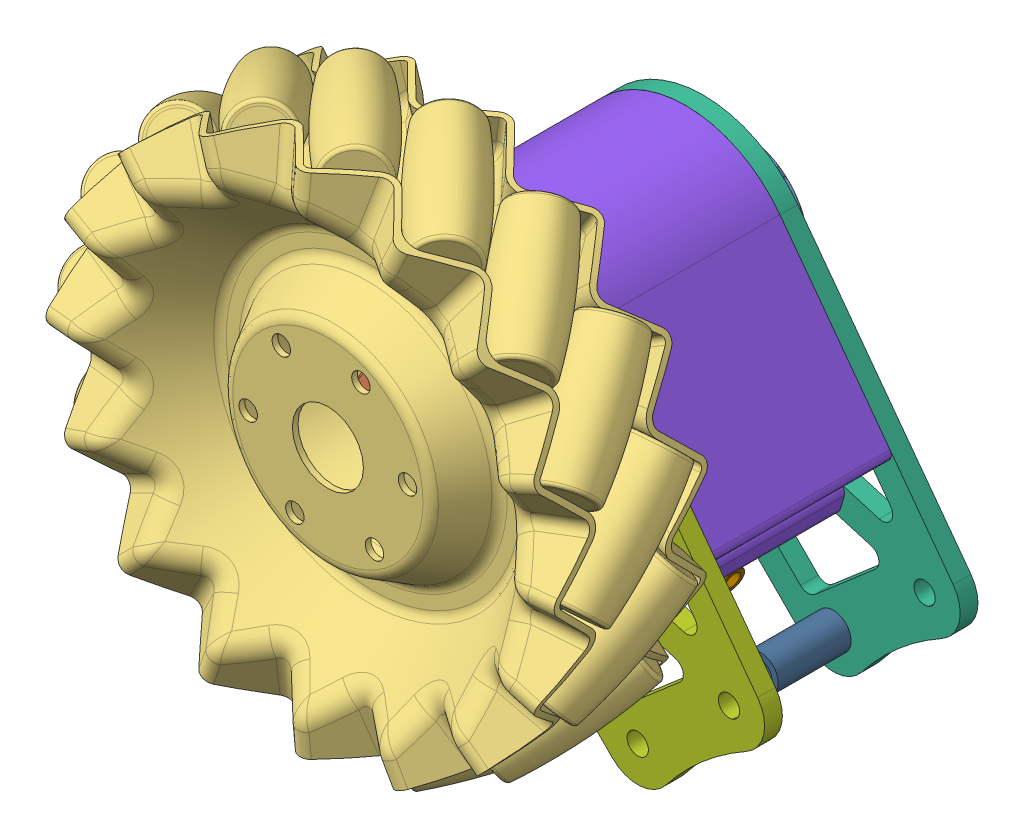
SolidWorks assembly 左旋轮系, configuration 默认. Lengths in mm.
Overall size (171.4 168.43 131.45).
12 component instances, 11 part files, 28 mates.
Components (placement in the parent):
- DP_RoboMaster GM3508无刷减速电机-2: DP_RoboMaster GM3508无刷减速电机 [默认] at origin size (42 44.98 98.4)
- DP_轮组端盖_1-2: DP_轮组端盖_1 [默认] at (34.8209 73.9788 45.5002) size (19.5 19.5 10)
- DP_左旋_mecanum_wheel-2: DP_左旋_mecanum_wheel [默认] at (55.7485 66.293 -72.6518) size (152.18 152.18 48.1)
- DP_轮毂挡板_1-2: DP_轮毂挡板_1 [默认] at (34.8209 73.9788 72.5004) x (0.995185 0.098017 0) z (0 0 1) size (54 54 3) (hidden)
- DP_夹紧联轴器2-3: DP_夹紧联轴器2 [默认] at (34.8209 73.9788 33.9) x (-0.925598 -0.378508 0) z (0 0 1) size (47.97 54.2 10)
- 51100推力球轴承-2: 51100推力球轴承 [默认] at (34.8209 73.9788 28.9) x (0.998906 -0.046769 0) z (0 0 1) size (24 24 10)
- 轮系支撑板 - 副-1: 轮系支撑板 - 副 [默认] at (34.8209 73.9788 -28.1) x (0.790596 -0.612338 0) z (0.612338 0.790596 0) size (128 5 76.21)
- 轮系支撑板-2: 轮系支撑板 [默认] at (34.8209 73.9788 26.9) x (0.790596 -0.612338 0) z (0.612338 0.790596 0) size (128 5 76.21)
- 轮组支撑打印件-2: 轮组支撑打印件 [默认] at (34.8209 73.9788 -3.1) x (0.790596 -0.612338 0) z (0.612338 0.790596 0) size (94.2 50 65.36)
- DP_C620无刷电机调速器-1: DP_C620无刷电机调速器 [默认] at (44.0175 32.8031 -3.1) x (-0.959567 0.281479 0) z (0 0 -1) size (103.05 11.5 26.13)
- 轮系套筒-1: 轮系套筒 [默认] at (76.3424 -0.1897 -28.1) size (10 10 20.5)
- 轮系套筒-2: 轮系套筒 [默认] at (76.3424 -0.1897 1.4) size (10 10 20.5)
Mates (geometry in assembly coordinates):
- 重合6: coincident anti-aligned: plane of DP_左旋_mecanum_wheel-2 through (34.8209 73.9788 72.5004) normal (0 0 1); plane of DP_轮毂挡板_1-2 through (34.8209 73.9788 72.5004) normal (0 0 -1)
- 同心11: concentric aligned: cylinder of DP_左旋_mecanum_wheel-2 through (34.8209 73.9788 83.574) axis (0 0 -1) radius 10; cylinder of DP_轮毂挡板_1-2 through (34.8209 73.9788 75.5004) axis (0 0 -1) radius 10.5
- 同心12: concentric aligned: cylinder of DP_左旋_mecanum_wheel-2 through (47.9266 55.6897 72.5004) axis (0 0 1) radius 2.6; cylinder of DP_轮毂挡板_1-2 through (47.9266 55.6897 72.5004) axis (0 0 1) radius 2.6
- 同心13: concentric aligned: cylinder of DP_轮组端盖_1-2 through (34.8209 73.9788 55.5002) axis (0 0 -1) radius 2.75; cylinder of DP_轮毂挡板_1-2 through (34.8209 73.9788 75.5004) axis (0 0 -1) radius 10.5
- 重合7: coincident anti-aligned: plane of DP_轮组端盖_1-2 through (34.8209 73.9788 45.5002) normal (0 0 -1); plane of DP_左旋_mecanum_wheel-2 through (34.8209 73.9788 45.5002) normal (0 0 1)
- 重合8: coincident anti-aligned: plane of DP_夹紧联轴器2-3 through (34.8209 73.9788 33.9) normal (0 0 -1); plane of 51100推力球轴承-2 through (34.8209 73.9788 33.9) normal (0 0 1)
- 同心14: concentric aligned: cylinder of DP_夹紧联轴器2-3 through (34.8209 73.9788 43.9) axis (0 0 -1) radius 5; cylinder of 51100推力球轴承-2 through (34.8209 73.9788 33.9) axis (0 0 -1) radius 5
- 同心15: concentric anti-aligned: cylinder of DP_RoboMaster GM3508无刷减速电机-2 through (34.8209 73.9788 49.2) axis (0 0 1) radius 5; cylinder of 51100推力球轴承-2 through (34.8209 73.9788 33.9) axis (0 0 -1) radius 12
- 重合9: coincident anti-aligned: plane of DP_RoboMaster GM3508无刷减速电机-2 through (36.0836 78.8167 29.2) normal (-0.378508 0.925598 0); plane of DP_夹紧联轴器2-3 through (36.0836 78.8167 43.9) normal (0.378508 -0.925598 0)
- 重合11: coincident anti-aligned: plane of DP_RoboMaster GM3508无刷减速电机-2 through (30.5655 63.8352 23.9) normal (0 0 1); plane of 51100推力球轴承-2 through (34.8209 73.9788 23.9) normal (0 0 -1)
- 同心16: concentric anti-aligned: cylinder of DP_RoboMaster GM3508无刷减速电机-2 through (34.8209 73.9788 49.2) axis (0 0 1) radius 5; cylinder of DP_轮组端盖_1-2 through (34.8209 73.9788 51.5002) axis (0 0 -1) radius 5.25
- 重合12: coincident anti-aligned: plane of DP_左旋_mecanum_wheel-2 through (34.8209 73.9788 43.9) normal (0 0 -1); plane of DP_夹紧联轴器2-3 through (57.1527 70.8487 43.9) normal (0 0 1)
- 重合13: coincident anti-aligned: plane of DP_RoboMaster GM3508无刷减速电机-2 through (29.7918 61.9909 21.9) normal (0 0 1); plane of 轮系支撑板-2 through (34.8209 73.9788 21.9) normal (0 0 -1)
- 同心17: concentric aligned: cylinder of DP_RoboMaster GM3508无刷减速电机-2 through (28.197 90.1768 21.9) axis (0 0 1) radius 1.65; cylinder of 轮系支撑板-2 through (28.197 90.1768 21.9) axis (0 0 1) radius 2.025
- 同心18: concentric aligned: cylinder of DP_RoboMaster GM3508无刷减速电机-2 through (41.4447 57.7808 21.9) axis (0 0 1) radius 1.65; cylinder of 轮系支撑板-2 through (41.4447 57.7808 21.9) axis (0 0 1) radius 2.025
- 同心19: concentric aligned: cylinder of 51100推力球轴承-2 through (34.8209 73.9788 33.9) axis (0 0 -1) radius 12; cylinder of 轮系支撑板 - 副-1 through (34.8209 73.9788 -23.1) axis (0 0 -1) radius 24
- 距离1: distance = 50 mm anti-aligned: plane of 轮系支撑板 - 副-1 through (34.8209 73.9788 -28.1) normal (0 0 1); plane of 轮系支撑板-2 through (34.8209 73.9788 21.9) normal (0 0 -1)
- 重合14: coincident aligned: plane of 轮系支撑板 - 副-1 through (11.4621 50.6685 -33.1) normal (-0.70784 -0.706373 0); plane of 轮系支撑板-2 through (11.4621 50.6685 21.9) normal (-0.70784 -0.706373 0)
- 重合16: coincident anti-aligned: plane of 轮系支撑板 - 副-1 through (34.8209 73.9788 -28.1) normal (0 0 1); plane of 轮组支撑打印件-2 through (34.8209 73.9788 -28.1) normal (0 0 -1)
- 同心22: concentric aligned: cylinder of 轮系支撑板 - 副-1 through (13.0619 90.8316 -38.1) axis (0 0 1) radius 1.525; cylinder of 轮组支撑打印件-2 through (13.0619 90.8316 -28.1) axis (0 0 1) radius 1.525
- 同心23: concentric aligned: cylinder of 轮系支撑板 - 副-1 through (17.968 52.2199 -38.1) axis (0 0 1) radius 1.525; cylinder of 轮组支撑打印件-2 through (17.968 52.2199 -28.1) axis (0 0 1) radius 1.525
- 重合17: coincident anti-aligned: plane of 轮组支撑打印件-2 through (25.948 43.7311 -18.1) normal (-0.281479 -0.959567 0); plane of DP_C620无刷电机调速器-1 through (47.1687 37.5063 -3.1) normal (0.281479 0.959567 0)
- 宽度1: width aligned: plane of 轮系支撑板-2 through (34.8209 73.9788 21.9) normal (0 0 -1); plane of DP_C620无刷电机调速器-1 through (34.8209 73.9788 -28.1) normal (0 0 1); plane of 轮系支撑板 - 副-1 through (24.2606 32.2416 -16) normal (0 0 -1); plane of DP_C620无刷电机调速器-1 through (24.2606 32.2416 9.8) normal (0 0 1)
- 重合18: coincident anti-aligned: line of 轮组支撑打印件-2 through (23.4674 44.4588 21.9) axis (0 0 -1); line of DP_C620无刷电机调速器-1 through (23.4674 44.4588 -12.1773) axis (0 0 1)
- 同心24: concentric aligned: cylinder of 轮系套筒——12份-1 through (76.3424 -0.1897 -7.6) axis (0 0 -1) radius 5; cylinder of 轮系套筒——12份-2 through (76.3424 -0.1897 21.9) axis (0 0 -1) radius 5
- 同心25: concentric anti-aligned: cylinder of 轮系支撑板-2 through (76.3424 -0.1897 21.9) axis (0 0 1) radius 3; cylinder of 轮系套筒——12份-1 through (76.3424 -0.1897 -7.6) axis (0 0 -1) radius 5
- 重合19: coincident anti-aligned: plane of 轮系支撑板 - 副-1 through (34.8209 73.9788 -28.1) normal (0 0 1); plane of 轮系套筒——12份-1 through (76.3424 -0.1897 -28.1) normal (0 0 -1)
- 重合20: coincident anti-aligned: plane of 轮系支撑板-2 through (34.8209 73.9788 21.9) normal (0 0 -1); plane of 轮系套筒——12份-2 through (76.3424 -0.1897 21.9) normal (0 0 1)
